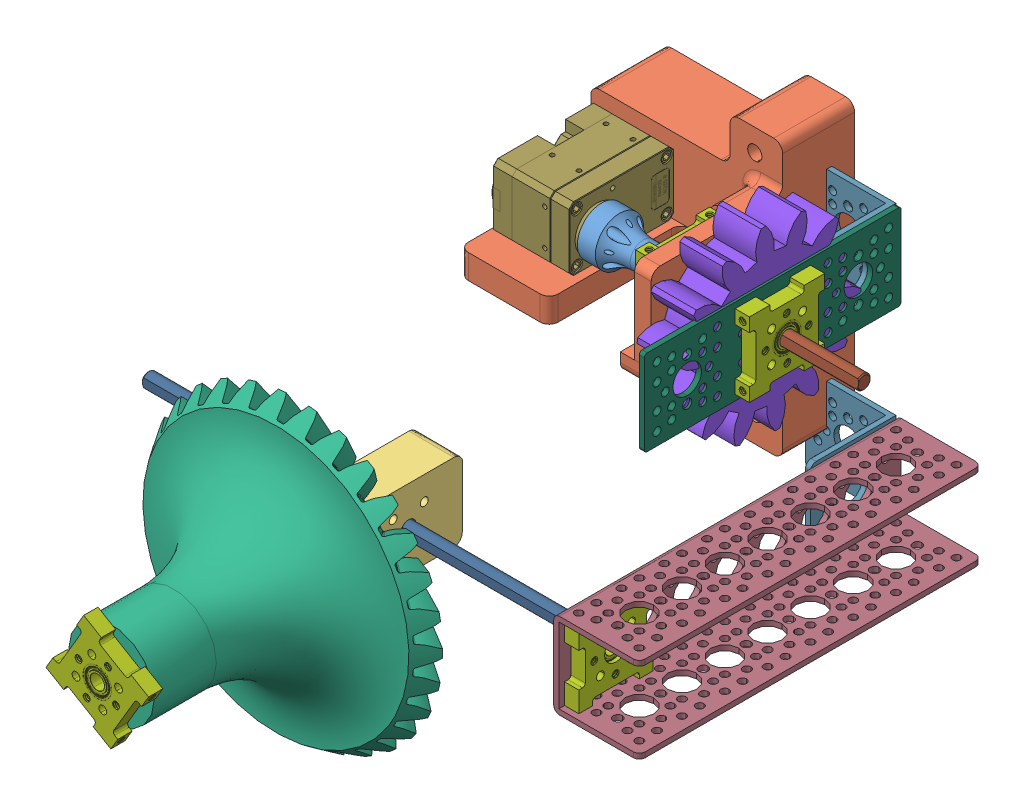
SolidWorks assembly ARMUS-REV2-000, configuration Défaut. Lengths in mm.
Overall size (242.52 216.56 271.76).
37 component instances, 23 part files, 58 mates.
Components (placement in the parent):
- ARMUS-REV2-002-1: ARMUS-REV2-002 [Default] at (141.0181 1031.7549 127.29) x (0 -0.988069 0.154009) z (0 0.154009 0.988069) size (22.05 28 22.05)
- ARMUS-REV2-004-1: ARMUS-REV2-004 [Défaut] at (117.9281 970.4739 75.3062) x (1 0 0) z (0 -1 0) size (85.41 90.57 122.11)
- ARMUS-REV2-005-1: ARMUS-REV2-005 [Défaut] at (157.9281 806.9641 75.3062) x (1 0 0) z (0 -1 0) size (85.41 90.57 122.11) (hidden)
- ARMUS-REV2-200-1: ARMUS-REV2-200 [Défaut] at (121.1548 967.4995 203.165) x (0 0 1) z (0.999969 -0.007812 0) size (54 35 20)
  - ARMUS-REV2-201-1: ARMUS-REV2-201 [Défaut] at origin size (54 35 20)
  - HUB-0_25-1: HUB-0_25 [Défaut] at (-30.0172 37.5992 -6.2696) x (-1 0 0) z (0 -1 0) size (25.4 12.7 25.4)
  - hex nut_ai-2: hex nut_ai [HNUT 0.2500-20-D-N] at (19.3798 17.5 0) x (0 0.5 0.866025) z (-1 0 0) size (11.11 12.83 5.74)
- ARMUS-REV2-300-1: ARMUS-REV2-300 [Default] at (197.2182 950 203.49) x (1 0 0) z (0 0.35014 -0.936697) size (57.21 161.95 162.56)
  - ARMUS-REV2-301-1: ARMUS-REV2-301 [Default] at origin size (50.86 161.95 162.56) (hidden)
  - Bore Side Tapped Pillow Block 1.25-1: Bore Side Tapped Pillow Block 1.25 [Default] at (-39.4159 7.6184 -28.3917) x (0 -1 0) z (0 0 1) size (33.54 6.35 33.02) (hidden)
  - Bore Side Tapped Pillow Block 1.25-2: Bore Side Tapped Pillow Block 1.25 [Default] at (4.8346 7.6184 -28.3917) x (0 -1 0) z (0 0 1) size (33.54 6.35 33.02) (hidden)
- ARMUS-REV2-400-1: ARMUS-REV2-400 [Défaut] at (121.0181 950 252.232) x (0 0 -1) z (-0.508464 -0.861083 0) size (99.55 130.43 130.79)
  - ARMUS-REV2-401-1: ARMUS-REV2-401 [Default] at origin size (93.2 130.43 130.79)
  - Bore Side Tapped Pillow Block 1.25-1: Bore Side Tapped Pillow Block 1.25 [Default] at (-58.9626 7.6184 28.3917) x (0 -1 0) z (0 0 -1) size (33.54 6.35 33.02)
  - Bore Side Tapped Pillow Block 1.25-2: Bore Side Tapped Pillow Block 1.25 [Default] at (26.0822 -28.3917 7.6184) x (0 0 -1) z (0 1 0) size (33.54 6.35 33.02)
- ARMUS-REV2-500-1: ARMUS-REV2-500 [Défaut] at (216.2682 1031.7548 127.289) x (-1 0 0) z (0 -0.682686 0.730712) size (28.58 79.69 81.28)
  - ARMUS-REV2-501-1: ARMUS-REV2-501 [Défaut] at origin size (19.05 79.69 81.28) (hidden)
  - bore_set_screw_D_hub-1: bore_set_screw_D_hub [Défaut] at (-20.7023 -52.5937 -16.7801) x (0 -1 0.000796) z (0 0.000796 1) size (20.57 9.61 20.57) (hidden)
- z_env_0-1: z_env_0 [Default] at origin size (200 1000 50) (hidden)
- hex bolt_ai-4: hex bolt_ai [HBOLT 0.2500-20x4.5x0.75-N] at (121.0181 950 336.7402) x (0 0 -1) z (0.923728 0.383049 0) size (119.08 12.85 11.13) (hidden)
- spur gear_ai-18: spur gear_ai [Inch - Spur gear 5DP 14T 20PA 0.75FW ---S14N3.0H2.0L0.5N] at (197.2182 1031.7549 127.29) x (1 0 0) z (0 0.145675 0.989332) size (19.05 79.69 81.28)
- ARMUS-REV2-100-1: ARMUS-REV2-100 [Défaut] at (197.2182 950 203.49) x (1 0 0) z (0 -0.986274 0.165118) size (50.86 161.95 162.56)
  - straight bevel pinion_ai-4: straight bevel pinion_ai [Inch - Straight bevel pinion 6DP20PT 30GT 20PA 0.75FW ---20O4H3MD0.5N] at (-9.9279 0 0) x (-1 0 0) z (0 0 -1) size (31.81 92.88 92.88) (hidden)
  - spur gear_ai-3: spur gear_ai [Inch - Spur gear 5DP 30T 20PA .75FW ---S30N3.0H2.0L0.5N] at origin size (19.05 161.95 162.56) (hidden)
- straight bevel gear_ai-7: straight bevel gear_ai [Inch - Straight bevel gear 6DP 30GT 20PT 20PA 0.75FW ---30O1.5H5.05MD0.5N] at (121.0181 950 252.232) x (0 0 -1) z (0.993195 -0.116459 0) size (99.55 130.43 130.79) (hidden)
- bore_set_screw_D_hub-1: bore_set_screw_D_hub [Défaut] at (90.1853 933.4177 255.7446) x (0 0 1) z (0.007812 0.999969 0) size (20.57 9.61 20.57)
- D-Shaft 1.25x8-1: D-Shaft 1.25x8 [Default] at (116.9936 950 203.49) x (0 1 0) z (-1 0 0) size (6.35 5.71 203.2)
- D-Shaft 1.25x6-1: D-Shaft 1.25x6 [Default] at (207.1181 1031.7549 127.29) x (0 0.988069 -0.154009) z (-1 0 0) size (6.35 5.71 101.6)
- Bore Side Tapped Pillow Block 1.25-1: Bore Side Tapped Pillow Block 1.25 [Default] at (237.8514 942.3816 175.0983) x (0 1 0) z (0 0 1) size (33.54 6.35 33.02)
- Bore Side Tapped Pillow Block 1.25-3: Bore Side Tapped Pillow Block 1.25 [Default] at (203.0706 1060.1466 134.9084) x (0 0 -1) z (0 -1 0) size (33.54 6.35 33.02)
- XM430-W350-R-1: XM430-W350-R [Default] at (121.6099 1032.2416 115.9655) x (0 1 0) z (1 0 0) size (28.5 46.5 41)
- Bore Side Tapped Pillow Block 1.25-6: Bore Side Tapped Pillow Block 1.25 [Default] at (193.2335 1024.1364 98.8983) x (0 1 0) z (0 0 1) size (33.54 6.35 33.02)
- Bore Side Tapped Pillow Block 1.25-7: Bore Side Tapped Pillow Block 1.25 [Default] at (48.8027 875.8636 98.8983) x (0 -1 0) z (0 0 1) size (33.54 6.35 33.02) (hidden)
- ARMUS-REV2-012-1: ARMUS-REV2-012 [Default] at (215 969.05 70.14) x (0 -1 0) z (0 0 1) size (38.1 38.1 152.4)
- ARMUS-REV2-010-1: ARMUS-REV2-010 [Default] at (195.95 950 70.14) x (0 1 0) z (1 0 0) size (38.1 38.1 38.1)
- ARMUS-REV2-011-3: ARMUS-REV2-011 [Default] at (215 1031.7549 146.34) x (0 0 1) z (0 1 0) size (114.3 2.29 38.1)
- ARMUS-REV2-010-2: ARMUS-REV2-010 [Default] at (195.95 1031.7549 70.14) x (0 1 0) z (1 0 0) size (38.1 38.1 38.1)
Mates (geometry in assembly coordinates):
- Coincident1: coordinate: point of z_env_0-1
- Concentric6: concentric anti-aligned: cylinder of D-Shaft 1.25x8-1 through (218.5936 950 203.49) axis (-1 0 0) radius 3.175; cylinder of Bore Side Tapped Pillow Block 1.25-1 through (217.2987 950 203.49) axis (1 0 0) radius 3.175
- Concentric33: concentric anti-aligned: cylinder of XM430-W350-R-1 through (143.0181 1031.7549 127.29) axis (1 0 0) radius 4; cylinder of spur gear_ai-18 through (248.0183 1031.7549 127.29) axis (-1 0 0) radius 6.35
- Coincident38: coincident anti-aligned: plane of XM430-W350-R-1 through (141.0181 1031.7549 127.29) normal (1 0 0); plane of ARMUS-REV2-002-1 through (141.0181 1031.7549 127.29) normal (-1 0 0)
- Concentric37: concentric: cylinder of XM430-W350-R-1 through (141.0181 1031.7549 127.29) axis (1 0 0) radius 9.75; cylinder of ARMUS-REV2-002-1 through (149.0181 1031.7549 127.29) axis (-1 0 0) radius 10.75
- Concentric38: concentric anti-aligned: cylinder of ARMUS-REV2-002-1 through (141.0171 1031.7549 127.29) axis (1 0 0) radius 3.375; cylinder of D-Shaft 1.25x6-1 through (257.9181 1031.7549 127.29) axis (-1 0 0) radius 3.175
- Parallel6: parallel anti-aligned: plane of ARMUS-REV2-002-1 through (141.0171 1034.0591 129.7039) normal (0 -0.154009 -0.988069); plane of D-Shaft 1.25x6-1 through (257.9181 1030.2638 130.0931) normal (0 0.154009 0.988069)
- Distance2: distance = 12.7 mm anti-aligned: plane of D-Shaft 1.25x6-1 through (156.3181 1031.7549 127.29) normal (-1 0 0); plane of ARMUS-REV2-002-1 through (169.0181 1031.7549 127.29) normal (1 0 0)
- Concentric39: concentric aligned: cylinder of Bore Side Tapped Pillow Block 1.25-3 through (223.6233 1031.7549 127.29) axis (-1 0 0) radius 3.175; cylinder of D-Shaft 1.25x6-1 through (257.9181 1031.7549 127.29) axis (-1 0 0) radius 3.175
- Parallel10: parallel anti-aligned: plane of D-Shaft 1.25x8-1 through (218.5936 948.095 206.03) normal (0 0 1); plane of straight bevel gear_ai-7 through (121.0181 950 240.0653) normal (0 0 -1)
- Concentric282: concentric anti-aligned: cylinder of D-Shaft 1.25x8-1 through (218.5936 950 203.49) axis (-1 0 0) radius 3.175; cylinder of ARMUS-REV2-100-1/straight bevel pinion_ai-4 through (111.0903 950 203.49) axis (1 0 0) radius 6.35
- GearMate4: gear = 25.4 : 50.8 mm: cylinder of straight bevel gear_ai-7 through (121.0181 950 331.7601) axis (0 0 -1) radius 19.05; cylinder of ARMUS-REV2-100-1/straight bevel pinion_ai-4 through (111.0903 950 203.49) axis (1 0 0) radius 6.35
- Coincident52: coincident: point of ?; point of straight bevel gear_ai-7
- Concentric283: concentric aligned: cylinder of D-Shaft 1.25x8-1 through (218.5936 950 203.49) axis (-1 0 0) radius 3.175; cylinder of ARMUS-REV2-100-1/spur gear_ai-3 through (248.0183 950 203.49) axis (-1 0 0) radius 6.35
- Width5: width aligned: plane of spur gear_ai-18 through (197.2182 1031.7549 127.29) normal (-1 0 0); plane of spur gear_ai-18 through (216.2682 1031.7549 127.29) normal (1 0 0); plane of ARMUS-REV2-100-1/spur gear_ai-3 through (197.2182 950 203.49) normal (-1 0 0); plane of ARMUS-REV2-100-1/spur gear_ai-3 through (216.2682 950 203.49) normal (1 0 0)
- Tangent4: tangent: circle of spur gear_ai-6; circle of ARMUS-REV2-100-1/spur gear_ai-2
- GearMate5: gear = 71.12 : 152.4 mm: circle of ARMUS-REV2-100-1/spur gear_ai-2; circle of spur gear_ai-6
- Coaxiale2: concentric aligned: cylinder of straight bevel gear_ai-7 through (121.0181 950 123.962) axis (0 0 1) radius 6.35; cylinder of ARMUS-REV2-200-1/ARMUS-REV2-201-1 through (121.0181 950 208.6847) axis (0 0 1) radius 3.175
- Parallèle1: parallel aligned: plane of D-Shaft 1.25x8-1 through (218.5936 948.095 206.03) normal (0 0 1); plane of straight bevel gear_ai-7 through (121.0181 950 252.232) normal (0 0 1)
- Coaxiale3: concentric aligned: cylinder of straight bevel gear_ai-7 through (121.0181 950 123.962) axis (0 0 1) radius 6.35; cylinder of hex bolt_ai-4 through (121.0181 950 336.7402) axis (0 0 1) radius 3.175
- Tangent6: tangent: circle of ARMUS-REV2-200-1/ARMUS-REV2-003-1; plane of hex bolt_ai-4 through (121.0181 950 217.665) normal (0 0 -1)
- Coaxiale4: concentric aligned: cylinder of D-Shaft 1.25x6-1 through (257.9181 1031.7549 127.29) axis (-1 0 0) radius 3.175; cylinder of ARMUS-REV2-004-1 through (219.4291 1031.7549 127.29) axis (-1 0 0) radius 4.5
- Distance3: distance = 25 mm anti-aligned: plane of ARMUS-REV2-004-1 through (163.0181 1050.5839 150.5666) normal (-1 0 0); plane of XM430-W350-R-1 through (138.0181 1046.0049 92.04) normal (1 0 0)
- Coaxiale5: concentric anti-aligned: cylinder of D-Shaft 1.25x6-1 through (257.9181 1031.7549 127.29) axis (-1 0 0) radius 3.175; cylinder of Bore Side Tapped Pillow Block 1.25-6 through (172.6808 1031.7549 127.29) axis (1 0 0) radius 3.175
- Coïncidente3: coincident anti-aligned: plane of ARMUS-REV2-004-1 through (179.0181 1012.5639 150.5666) normal (-1 0 0); plane of Bore Side Tapped Pillow Block 1.25-6 through (179.0181 1031.7549 127.29) normal (1 0 0)
- Parallèle4: parallel aligned: plane of ARMUS-REV2-004-1 through (163.0181 1050.5839 150.5666) normal (0 1 0); plane of Bore Side Tapped Pillow Block 1.25-6 through (172.6681 1048.5189 116.876) normal (0 1 0)
- Coaxiale17: concentric aligned: cylinder of ARMUS-REV2-005-1 through (55.6081 875.1599 134.2048) axis (1 0 0) radius 1.778; cylinder of Bore Side Tapped Pillow Block 1.25-7 through (69.3681 875.1599 134.2048) axis (1 0 0) radius 1.778
- Coïncidente14: coincident anti-aligned: plane of ARMUS-REV2-005-1 through (63.0181 849.0541 150.5666) normal (1 0 0); plane of Bore Side Tapped Pillow Block 1.25-7 through (63.0181 868.2451 127.29) normal (-1 0 0)
- Concentric289: concentric aligned: cylinder of ARMUS-REV2-100-1/spur gear_ai-3 through (248.0183 950 203.49) axis (-1 0 0) radius 6.35; cylinder of ARMUS-REV2-300-1/Bore Side Tapped Pillow Block 1.25-2 through (222.6055 950 203.49) axis (-1 0 0) radius 3.175
- Concentric290: concentric aligned: cylinder of ARMUS-REV2-100-1/spur gear_ai-3 through (216.2682 949.6347 131.8864) axis (-1 0 0) radius 30.48; cylinder of ARMUS-REV2-300-1/ARMUS-REV2-301-1 through (216.2682 949.6347 131.8864) axis (-1 0 0) radius 30.48
- Coincident55: coincident aligned: plane of ARMUS-REV2-100-1/spur gear_ai-3 through (216.2682 950 203.49) normal (1 0 0); plane of ARMUS-REV2-300-1/ARMUS-REV2-301-1 through (216.2682 950 203.49) normal (1 0 0)
- Concentric298: concentric aligned: cylinder of ARMUS-REV2-400-1/ARMUS-REV2-401-1 through (121.0181 950 123.962) axis (0 0 1) radius 6.35; cylinder of straight bevel gear_ai-7 through (121.0181 950 123.962) axis (0 0 1) radius 6.35
- Coincident60: coincident aligned: plane of straight bevel gear_ai-7 through (121.0181 950 240.0653) normal (0 0 -1); plane of ARMUS-REV2-400-1/ARMUS-REV2-401-1 through (121.0181 950 240.0653) normal (0 0 -1)
- Concentric299: concentric anti-aligned: cylinder of hex bolt_ai-4 through (121.0181 950 336.7402) axis (0 0 1) radius 3.175; cylinder of ARMUS-REV2-400-1/Bore Side Tapped Pillow Block 1.25-1 through (121.0181 950 331.7474) axis (0 0 -1) radius 3.175
- Concentric304: concentric anti-aligned: cylinder of ARMUS-REV2-200-1/ARMUS-REV2-201-1 through (106.0436 957.032 196.2502) axis (0.999969 -0.007812 0) radius 1.778; cylinder of bore_set_screw_D_hub-1 through (111.0724 956.9927 196.2502) axis (-0.999969 0.007812 0) radius 3.3722
- Concentric305: concentric anti-aligned: cylinder of ARMUS-REV2-200-1/ARMUS-REV2-201-1 through (106.0436 957.032 210.0797) axis (0.999969 -0.007812 0) radius 1.778; cylinder of bore_set_screw_D_hub-1 through (111.0724 956.9927 210.0797) axis (-0.999969 0.007812 0) radius 3.3722
- Coincident65: coincident anti-aligned: plane of ARMUS-REV2-200-1/ARMUS-REV2-201-1 through (110.8817 932.5787 233.165) normal (-0.999969 0.007812 0); plane of bore_set_screw_D_hub-1 through (110.9914 946.6208 199.7076) normal (0.999969 -0.007812 0)
- Coincident66: coincident aligned: plane of spur gear_ai-18 through (197.2182 1031.7549 127.29) normal (-1 0 0); plane of ARMUS-REV2-500-1/ARMUS-REV2-501-1 through (197.2182 1031.7548 127.289) normal (-1 0 0)
- Concentric306: concentric aligned: cylinder of D-Shaft 1.25x6-1 through (257.9181 1031.7549 127.29) axis (-1 0 0) radius 3.175; cylinder of ARMUS-REV2-500-1/bore_set_screw_D_hub-1 through (216.2682 1031.7548 127.29) axis (-1 0 0) radius 3.175
- Coincident67: coincident anti-aligned: circle of spur gear_ai-18; circle of ARMUS-REV2-500-1/ARMUS-REV2-501-1
- Concentric308: concentric anti-aligned: cylinder of ARMUS-REV2-012-1 through (215 950 89.19) axis (-1 0 0) radius 6.3627; cylinder of ARMUS-REV2-010-1 through (215 950 89.19) axis (1 0 0) radius 6.3627
- Coincident71: coincident aligned: plane of ARMUS-REV2-012-1 through (215 969.05 70.14) normal (0 0 -1); plane of ARMUS-REV2-010-1 through (195.95 950 70.14) normal (0 0 -1)
- Concentric312: concentric aligned: cylinder of ARMUS-REV2-500-1/ARMUS-REV2-501-1 through (165.4682 1031.7548 127.289) axis (1 0 0) radius 6.35; cylinder of ARMUS-REV2-011-3 through (217.286 1031.7549 127.29) axis (1 0 0) radius 6.3627
- Coincident77: coincident aligned: plane of ARMUS-REV2-012-1 through (215 969.05 70.14) normal (0 0 -1); plane of ARMUS-REV2-011-3 through (161.1185 1012.7049 70.14) normal (0 0 -1)
- Coincident78: coincident aligned: plane of ARMUS-REV2-012-1 through (215 930.95 222.54) normal (-1 0 0); plane of ARMUS-REV2-011-3 through (215 1031.7549 146.34) normal (-1 0 0)
- Coincident79: coincident anti-aligned: plane of ARMUS-REV2-011-3 through (215 1031.7549 146.34) normal (-1 0 0); plane of ARMUS-REV2-010-2 through (215 1012.7049 72.426) normal (1 0 0)
- Concentric313: concentric aligned: cylinder of ARMUS-REV2-011-3 through (217.286 1031.7549 89.19) axis (1 0 0) radius 6.3627; cylinder of ARMUS-REV2-010-2 through (215 1031.7549 89.19) axis (1 0 0) radius 6.3627
- Coincident80: coincident aligned: plane of ARMUS-REV2-010-1 through (195.95 950 70.14) normal (0 0 -1); plane of ARMUS-REV2-010-2 through (195.95 1031.7549 70.14) normal (0 0 -1)
- Coincident81: coincident anti-aligned: plane of ARMUS-REV2-012-1 through (215 930.95 222.54) normal (-1 0 0); plane of ARMUS-REV2-010-1 through (215 930.95 72.426) normal (1 0 0)
- Distance6: distance = 129.714 mm: plane of XM430-W350-R-1 through (104.0181 1046.0049 92.04) normal (-1 0 0); plane of ARMUS-REV2-010-2 through (212.714 1031.7549 70.14) normal (-1 0 0)
- Concentric316: concentric aligned: cylinder of Bore Side Tapped Pillow Block 1.25-1 through (217.286 943.0852 210.4048) axis (-1 0 0) radius 1.778; cylinder of ARMUS-REV2-012-1 through (215 943.0852 210.4048) axis (-1 0 0) radius 1.778
- Concentric317: concentric aligned: cylinder of Bore Side Tapped Pillow Block 1.25-1 through (217.286 956.9148 210.4048) axis (-1 0 0) radius 1.778; cylinder of ARMUS-REV2-012-1 through (215 956.9148 210.4048) axis (-1 0 0) radius 1.778
- Coincident84: coincident anti-aligned: plane of Bore Side Tapped Pillow Block 1.25-1 through (217.286 950 203.49) normal (-1 0 0); plane of ARMUS-REV2-012-1 through (217.286 966.764 222.54) normal (1 0 0)
- Concentric318: concentric aligned: cylinder of Bore Side Tapped Pillow Block 1.25-3 through (223.636 1038.6697 134.2048) axis (1 0 0) radius 1.778; cylinder of ARMUS-REV2-011-3 through (217.286 1038.6697 134.2048) axis (1 0 0) radius 1.778
- Concentric319: concentric aligned: cylinder of Bore Side Tapped Pillow Block 1.25-3 through (223.636 1024.8401 134.2048) axis (1 0 0) radius 1.778; cylinder of ARMUS-REV2-011-3 through (217.286 1024.8401 134.2048) axis (1 0 0) radius 1.778
- Coincident85: coincident anti-aligned: plane of Bore Side Tapped Pillow Block 1.25-3 through (217.286 1031.7549 127.29) normal (-1 0 0); plane of ARMUS-REV2-011-3 through (217.286 1031.7549 146.34) normal (1 0 0)
- Parallel12: parallel aligned: plane of ARMUS-REV2-004-1 through (121.0181 950 60) normal (0 0 -1); plane of ARMUS-REV2-010-2 through (195.95 1031.7549 70.14) normal (0 0 -1)
- Parallel13: parallel aligned: plane of ARMUS-REV2-004-1 through (121.0181 950 60) normal (0 0 -1); plane of ARMUS-REV2-005-1 through (121.0181 786.4903 60) normal (0 0 -1)
